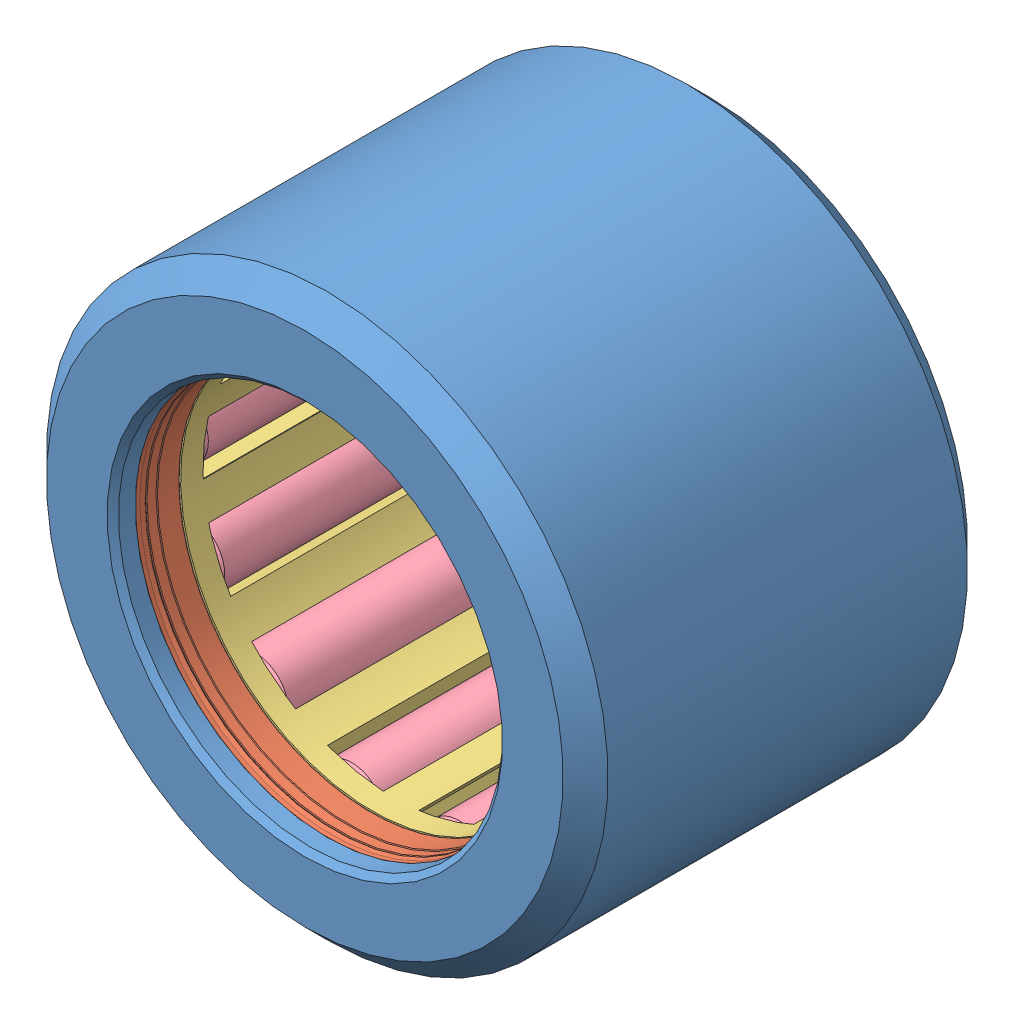
SolidWorks assembly GR, configuration Default. Lengths in mm.
Overall size (25 25 18).
17 component instances, 4 part files, 10 mates.
Components (placement in the parent):
- Parte1GR-1: Parte1GR [Default] at (3.08 -0.8253 25.2904) size (25 25 18)
- Parte2GR-1: Parte2GR [Default] at (3.08 -0.8253 25.2904) x (0 0 -1) z (1 0 0) size (1.98 23 23)
- Parte2GR-2: Parte2GR [Default] at (3.08 -0.8253 25.2904) x (0 0 1) z (-1 0 0) size (1.98 23 23)
- Parte3GR-1: Parte3GR [Default] at (3.08 -0.8253 25.2722) x (0 0 -1) z (0.999496 0.031758 0) size (12 20 20)
- Parte4GR-1: Parte4GR [Default] at (0.9964 -10.6058 25.2722) x (1 0.000159 0) z (0 0 1) size (3 3 10)
- Parte4GR-14: Parte4GR [Default] at (-3.3102 -8.5172 25.2722) x (0.88553 -0.464582 0) z (0 0 1) size (3 3 10)
- Parte4GR-15: Parte4GR [Default] at (-6.1528 -4.6665 25.2722) x (0.568196 -0.822893 0) z (0 0 1) size (3 3 10)
- Parte4GR-16: Parte4GR [Default] at (-6.8804 0.0642 25.2722) x (0.120695 -0.99269 0) z (0 0 1) size (3 3 10)
- Parte4GR-17: Parte4GR [Default] at (-5.3261 4.5911 25.2722) x (-0.354456 -0.935073 0) z (0 0 1) size (3 3 10)
- Parte4GR-18: Parte4GR [Default] at (-1.8461 7.8772 25.2722) x (-0.748405 -0.663242 0) z (0 0 1) size (3 3 10)
- Parte4GR-19: Parte4GR [Default] at (2.7624 9.1696 25.2722) x (-0.970904 -0.23947 0) z (0 0 1) size (3 3 10)
- Parte4GR-20: Parte4GR [Default] at (7.4437 8.1724 25.2722) x (-0.97098 0.239161 0) z (0 0 1) size (3 3 10)
- Parte4GR-21: Parte4GR [Default] at (11.1253 5.1138 25.2722) x (-0.748616 0.663003 0) z (0 0 1) size (3 3 10)
- Parte4GR-22: Parte4GR [Default] at (12.9638 0.6947 25.2722) x (-0.354754 0.93496 0) z (0 0 1) size (3 3 10)
- Parte4GR-23: Parte4GR [Default] at (12.538 -4.0726 25.2722) x (0.120378 0.992728 0) z (0 0 1) size (3 3 10)
- Parte4GR-24: Parte4GR [Default] at (9.9456 -8.0961 25.2722) x (0.567934 0.823074 0) z (0 0 1) size (3 3 10)
- Parte4GR-25: Parte4GR [Default] at (5.7803 -10.4538 25.2722) x (0.885382 0.464864 0) z (0 0 1) size (3 3 10)
Mates (geometry in assembly coordinates):
- Coincidente1: coincident anti-aligned: plane of Parte1GR-1 through (3.08 10.6747 17.2904) normal (0 0 1); plane of Parte2GR-2 through (3.08 8.4975 17.2904) normal (0 0 -1)
- Concentrico1: concentric aligned: cylinder of Parte1GR-1 through (3.08 -0.8253 25.2904) axis (0 0 1) radius 11.5; cylinder of Parte2GR-2 through (3.08 -0.8253 25.2904) axis (0 0 1) radius 11.5
- Coincidente2: coincident anti-aligned: plane of Parte1GR-1 through (3.08 7.7247 33.2904) normal (0 0 -1); plane of Parte2GR-1 through (3.08 8.4975 33.2904) normal (0 0 1)
- Concentrico2: concentric anti-aligned: cylinder of Parte1GR-1 through (3.08 -0.8253 25.2904) axis (0 0 1) radius 11.5; cylinder of Parte2GR-1 through (3.08 -0.8253 25.2904) axis (0 0 -1) radius 11.5
- Concentrico3: concentric anti-aligned: cylinder of Parte1GR-1 through (3.08 -0.8253 25.2904) axis (0 0 1) radius 11.5; cylinder of Parte3GR-1 through (3.08 -0.8253 25.2722) axis (0 0 -1) radius 10
- Coincidente3: coincident anti-aligned: plane of Parte2GR-2 through (3.08 10.6247 19.2722) normal (0 0 1); plane of Parte3GR-1 through (2.7624 9.1696 19.2722) normal (0 0 -1)
- Coincidente4: coincident anti-aligned: plane of Parte3GR-1 through (5.7803 -10.4538 20.2722) normal (0 0 1); plane of Parte4GR-1 through (0.9964 -10.6058 20.2722) normal (0 0 -1)
- Tangente1: tangent anti-aligned: plane of Parte3GR-1 through (2.4635 -10.9184 20.2722) normal (-0.978052 0.20836 0); cylinder of Parte4GR-1 through (0.9964 -10.6058 20.2722) axis (0 0 1) radius 1.5
- Tangente4: tangent aligned: cylinder of Parte1GR-1 through (3.08 -0.8253 25.2904) axis (0 0 1) radius 11.5; cylinder of Parte4GR-1 through (0.9964 -10.6058 20.2722) axis (0 0 1) radius 1.5
- AccoppiaIngranaggi1: gear = 23 : 3 mm: cylinder of Parte4GR-1 through (0.9964 -10.6058 20.2722) axis (0 0 1) radius 1.5; cylinder of Parte1GR-1 through (3.08 -0.8253 25.2904) axis (0 0 1) radius 11.5
